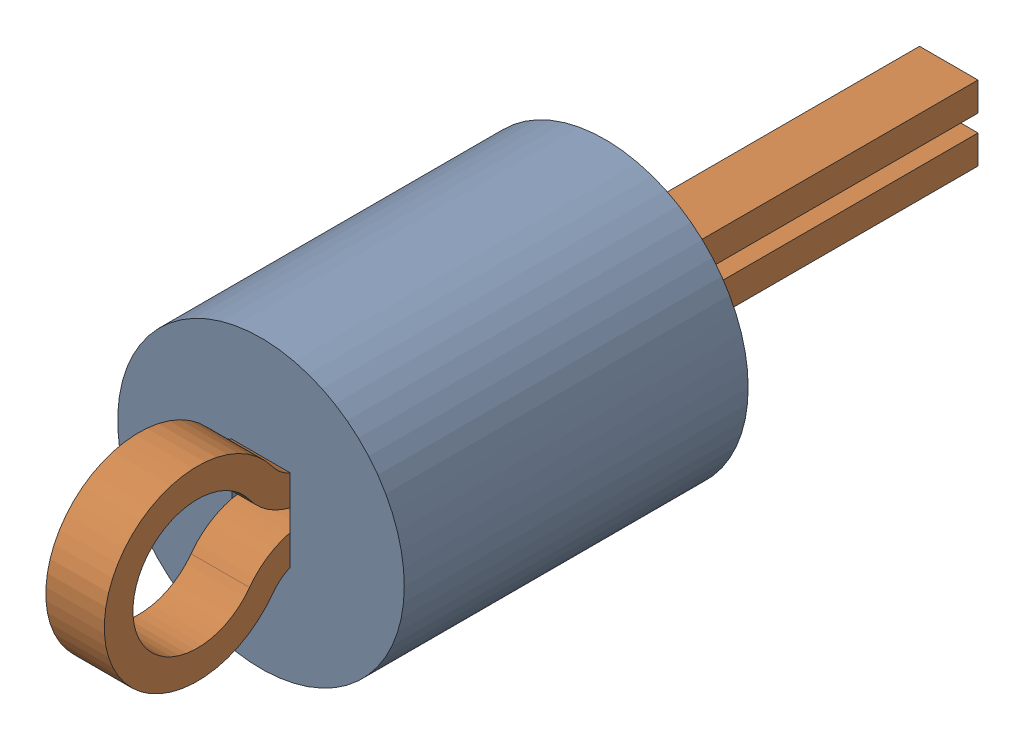
SolidWorks assembly TP5, configuration Default. Lengths in mm.
Overall size (2.5 2.5 7.62).
3 component instances, 2 part files, 0 mates.
Components (placement in the parent):
- Keystone_5002-1: Keystone_5002 [Default] at (27.9355 48.7709 0) size (2.5 2.5 7.62)
  - Keystone5002_white-1: Keystone5002_white [Default] at origin size (2.5 2.5 3)
  - Keystone500x_wire-1: Keystone500x_wire [Default] at origin size (0.51 1.62 7.62)
